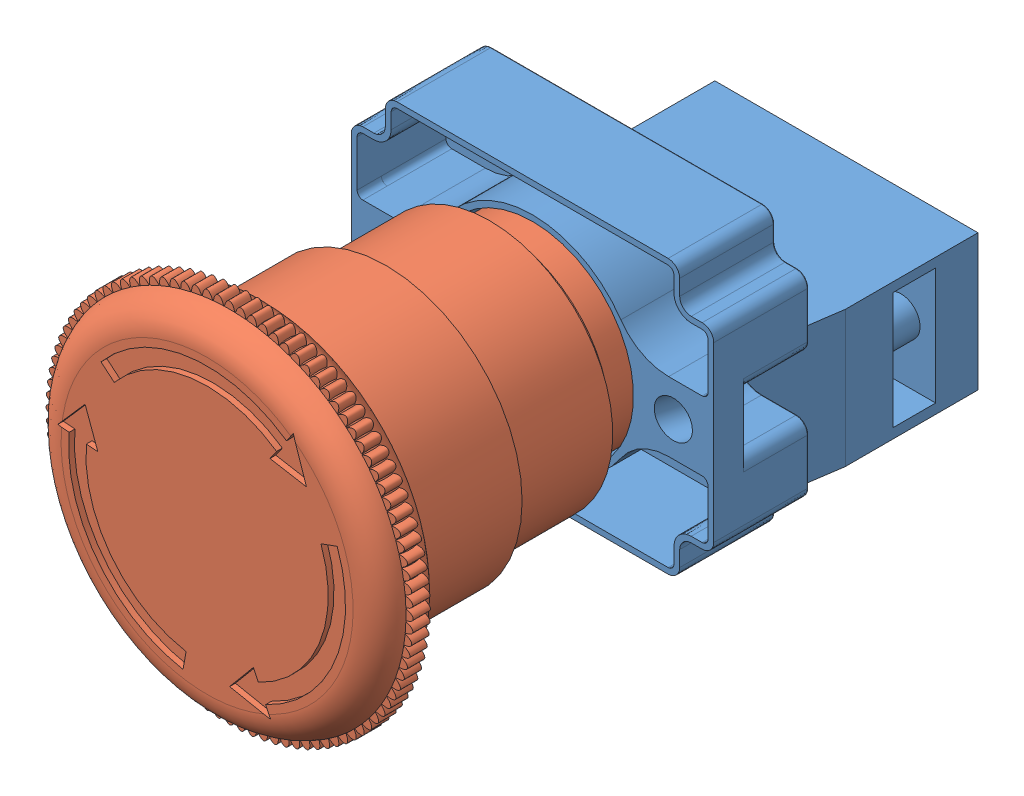
SolidWorks assembly E-Stop_Assembled, configuration Default. Lengths in mm.
Overall size (41.27 41.27 70.36).
3 component instances, 2 part files, 0 mates.
Components (placement in the parent):
- E-Stop_Assembled.stp-1: E-Stop_Assembled.stp [Default] at origin size (41.27 41.27 70.36)
  - E-Stop Base^E-Stop_Assembled.stp-1: E-Stop Base^E-Stop_Assembled.stp [Default] x (1 0 0) z (0 1 0) size (39.88 34.54 30.1)
  - E-Stop Button^E-Stop_Assembled.stp-1: E-Stop Button^E-Stop_Assembled.stp [Default] at (0 0 -10.414) x (1 0 0) z (0 -1 0) size (41.27 46.23 41.27)
